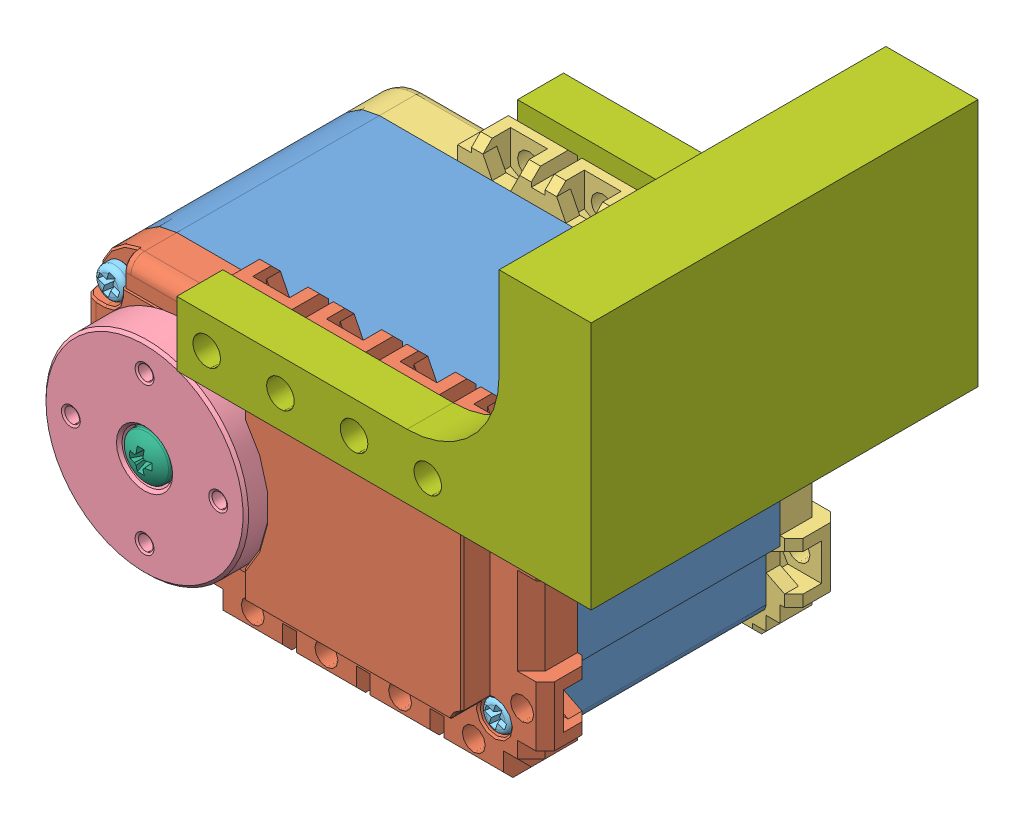
SolidWorks assembly ass_support_couder, configuration Défaut. Lengths in mm.
Overall size (60 53 42.55).
11 component instances, 7 part files, 3 mates.
Components (placement in the parent):
- AX-12A-1: AX-12A [Default] at (-10.3691 2.2968 48.7272) size (50 32 40.55)
  - AX-12A-01-1: AX-12A-01 [Default] at origin size (48.5 26 22)
  - AX-12A-02-1: AX-12A-02 [Default] at (0 0 13.5) size (50 32 8)
  - AX-12A-03-1: AX-12A-03 [Default] at (0 0 -13.5) x (1 0 0) z (0 0 -1) size (50 32 8)
  - AX-12A-04-1: AX-12A-04 [Default] at (0 0 21) size (22 22 6.7)
  - SetScrew-5: SetScrew [Default] at (33 10.4 14.5) x (0.31498 0.949098 0) z (0 0 -1) size (3.3 3.3 29.44)
  - SetScrew-6: SetScrew [Default] at (-9 9.25 14.5) x (0.31498 0.949098 0) z (0 0 -1) size (3.3 3.3 29.44)
  - SetScrew-7: SetScrew [Default] at (-9 -9.25 14.5) x (-0.958559 0.284893 0) z (0 0 -1) size (3.3 3.3 29.44)
  - SetScrew-8: SetScrew [Default] at (33 -10.4 14.5) x (0.31498 0.949098 0) z (0 0 -1) size (3.3 3.3 29.44)
  - pan head cross recess screw_iso-1: pan head cross recess screw_iso [ISO 7045 - M2.5 x 8 - Z --- 8C] at (0 0 21.6) x (0 0 -1) z (1 0 0) size (10.05 5 5)
- support_couder-1: support_couder [Défaut] at (28.1309 12.2968 69.7272) x (-1 0 0) z (0 0 -1) size (45 27 42)
Mates (geometry in assembly coordinates):
- Coaxiale1: concentric anti-aligned: cylinder of AX-12A-1/AX-12A-02-1 through (20.3809 15.7968 59.7262) axis (0 0 1) radius 1.25; cylinder of support_couder-1 through (20.3809 15.7968 69.7272) axis (0 0 -1) radius 1.5
- Coaxiale2: concentric anti-aligned: cylinder of AX-12A-1/AX-12A-02-1 through (-3.6191 15.7968 59.7262) axis (0 0 1) radius 1.25; cylinder of support_couder-1 through (-3.6191 15.7968 69.7272) axis (0 0 -1) radius 1.5
- Coïncidente1: coincident anti-aligned: plane of AX-12A-1/AX-12A-02-1 through (-10.3691 2.2968 64.7272) normal (0 0 1); plane of support_couder-1 through (-6.8691 12.2968 64.7272) normal (0 0 -1)
